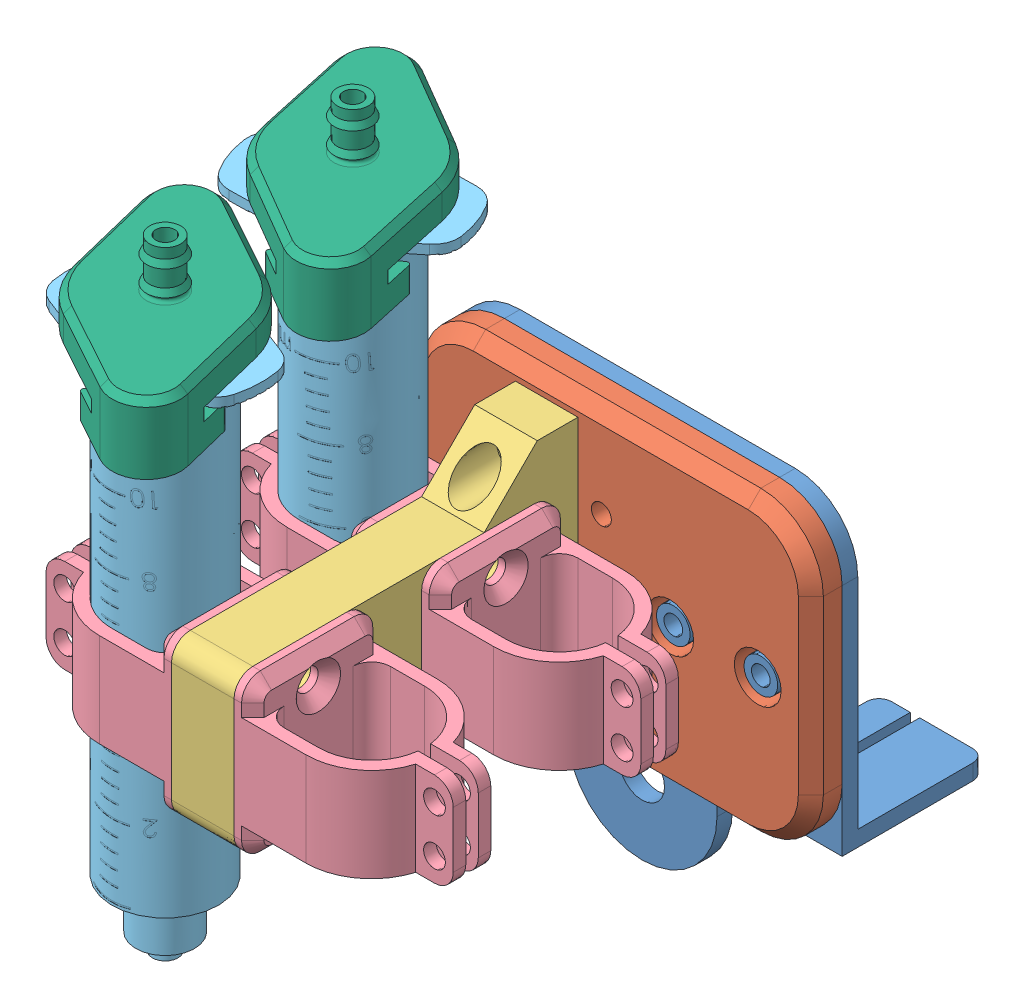
SolidWorks assembly quad-syringe, configuration Default. Lengths in mm.
Overall size (81.52 103.23 96.96).
11 component instances, 6 part files, 25 mates.
Components (placement in the parent):
- ender-3-bracket-1: ender-3-bracket [Default] at origin size (64 64 27.4)
- ender-3-quad-mount-1: ender-3-quad-mount [Default] at (37.5919 51.2294 2.5) x (1 0 0) z (0 -1 0) size (64 5 47.5)
- ender-3-syringe-mount-1: ender-3-syringe-mount [Default] at (-10.25 8.2 7.5) x (1 0 0) z (0 -1 0) size (10 55 42)
- syringe-holder-10ml-alt-1: syringe-holder-10ml-alt [Default] at (-15.25 8.2 52) x (0 0 1) z (-1 0 0) size (21 25 27.56)
- syringe-holder-10ml-alt-2: syringe-holder-10ml-alt [Default] at (-15.25 8.2 22) x (0 0 1) z (-1 0 0) size (21 25 27.56)
- syringe-holder-10ml-alt-3: syringe-holder-10ml-alt [Default] at (-5.25 8.2 22) x (0 0 -1) z (1 0 0) size (21 25 27.56)
- syringe-holder-10ml-alt-4: syringe-holder-10ml-alt [Default] at (-5.25 8.2 52) x (0 0 -1) z (1 0 0) size (21 25 27.56)
- syringe-cylinder-10ml-1: syringe-cylinder-10ml [Default] at (-26.75 53.3373 52) x (0 -1 0) z (-0.039342 0 0.999226) size (86.5 31 20)
- syringe-adapter-10ml-v3-1: syringe-adapter-10ml-v3 [Default] at (-26.75 58.3373 52) x (0.793052 0 -0.609153) z (0.609153 0 0.793052) size (24 18.62 43.5)
- syringe-cylinder-10ml-2: syringe-cylinder-10ml [Default] at (-26.75 57.4472 22) x (0 -1 0) z (0.339425 0 0.940633) size (86.5 31 20)
- syringe-adapter-10ml-v3-2: syringe-adapter-10ml-v3 [Default] at (-26.75 62.4472 22) x (0.808514 0 -0.588477) z (0.588477 0 0.808514) size (24 18.62 43.5)
Mates (geometry in assembly coordinates):
- Coincident2: coincident anti-aligned: plane of ender-3-bracket-1 through (0 -20 2.5) normal (0 0 1); plane of ender-3-quad-mount-1 through (37.5919 51.2294 2.5) normal (0 0 -1)
- Parallel1: parallel anti-aligned: plane of ender-3-quad-mount-1 through (37.5919 51.2294 2.5) normal (0 -1 0)
- Coincident4: coincident anti-aligned: plane of ender-3-quad-mount-1 through (37.5919 51.2294 7.5) normal (0 0 1); plane of ender-3-syringe-mount-1 through (-10.25 8.2 7.5) normal (0 0 -1)
- Concentric1: concentric anti-aligned: cylinder of ender-3-quad-mount-1 through (-10.25 24.2 7.5) axis (0 0 -1) radius 1.6; cylinder of ender-3-syringe-mount-1 through (-10.25 24.2 7.5) axis (0 0 1) radius 1.75
- Concentric2: concentric anti-aligned: cylinder of ender-3-quad-mount-1 through (-10.25 -7.8 7.5) axis (0 0 -1) radius 1.6; cylinder of ender-3-syringe-mount-1 through (-10.25 -7.8 7.5) axis (0 0 1) radius 1.75
- Coincident5: coincident anti-aligned: plane of ender-3-syringe-mount-1 through (-15.25 29.2 10.5) normal (-1 0 0); plane of syringe-holder-10ml-alt-1 through (-15.25 8.2 52) normal (1 0 0)
- Coincident6: coincident aligned: plane of ender-3-bracket-1 through (-32 0 0) normal (-1 0 0); plane of ender-3-quad-mount-1 through (-32 32 7.5) normal (-1 0 0)
- Coincident7: coincident aligned: plane of ender-3-bracket-1 through (-12 32 2.5) normal (0 1 0); plane of ender-3-quad-mount-1 through (-32 32 7.5) normal (0 1 0)
- Coincident8: coincident aligned: plane of ender-3-syringe-mount-1 through (-10.25 8.2 62.5) normal (0 0 1); plane of syringe-holder-10ml-alt-1 through (-18.25 20.7 62.5) normal (0 0 1)
- Coincident9: coincident aligned: plane of ender-3-syringe-mount-1 through (-15.25 20.7 62.5) normal (0 1 0); plane of syringe-holder-10ml-alt-1 through (-18.25 20.7 41.5) normal (0 1 0)
- Coincident10: coincident anti-aligned: plane of ender-3-syringe-mount-1 through (-15.25 29.2 10.5) normal (-1 0 0); plane of syringe-holder-10ml-alt-2 through (-15.25 8.2 22) normal (1 0 0)
- Coincident12: coincident aligned: plane of ender-3-syringe-mount-1 through (-15.25 20.7 62.5) normal (0 1 0); plane of syringe-holder-10ml-alt-2 through (-18.25 20.7 11.5) normal (0 1 0)
- Coincident13: coincident aligned: plane of syringe-holder-10ml-alt-3 through (-5.25 8.2 22) normal (-1 0 0); plane of syringe-holder-10ml-alt-4 through (-5.25 8.2 52) normal (-1 0 0)
- Coincident14: coincident anti-aligned: plane of ender-3-syringe-mount-1 through (-5.25 29.2 10.5) normal (1 0 0); plane of syringe-holder-10ml-alt-3 through (-5.25 8.2 22) normal (-1 0 0)
- Coincident15: coincident aligned: plane of syringe-holder-10ml-alt-3 through (-2.25 20.7 32.5) normal (0 1 0); plane of syringe-holder-10ml-alt-4 through (-2.25 20.7 62.5) normal (0 1 0)
- Coincident16: coincident aligned: plane of ender-3-syringe-mount-1 through (-10.25 8.2 62.5) normal (0 0 1); plane of syringe-holder-10ml-alt-4 through (-2.25 20.7 62.5) normal (0 0 1)
- Coincident18: coincident aligned: plane of ender-3-syringe-mount-1 through (-15.25 20.7 62.5) normal (0 1 0); plane of syringe-holder-10ml-alt-4 through (-2.25 20.7 62.5) normal (0 1 0)
- Concentric3: concentric anti-aligned: cylinder of syringe-holder-10ml-alt-1 through (-26.75 0.7 52) axis (0 1 0) radius 8.5; cylinder of syringe-cylinder-10ml-1 through (-26.75 -50.1842 52) axis (0 -1 0) radius 8.5
- Coincident19: coincident anti-aligned: plane of syringe-cylinder-10ml-1 through (-19.4557 53.3373 52.2872) normal (0 1 0); plane of syringe-adapter-10ml-v3-1 through (-25.8363 53.3373 53.1896) normal (0 -1 0)
- Concentric4: concentric anti-aligned: cylinder of syringe-cylinder-10ml-1 through (-26.75 -50.1842 52) axis (0 -1 0) radius 8.5; cylinder of syringe-adapter-10ml-v3-1 through (-26.75 66.2173 52) axis (0 1 0) radius 2.5
- Concentric5: concentric anti-aligned: cylinder of ender-3-syringe-mount-1 through (-5.25 15.7 22) axis (-1 0 0) radius 2; cylinder of syringe-holder-10ml-alt-2 through (-18.25 15.7 22) axis (1 0 0) radius 1.75
- Concentric6: concentric anti-aligned: cylinder of syringe-holder-10ml-alt-2 through (-26.75 0.7 22) axis (0 1 0) radius 8.5; cylinder of syringe-cylinder-10ml-2 through (-26.75 -46.0743 22) axis (0 -1 0) radius 8.5
- Concentric7: concentric anti-aligned: cylinder of syringe-cylinder-10ml-2 through (-26.75 -46.0743 22) axis (0 -1 0) radius 8.5; cylinder of syringe-adapter-10ml-v3-2 through (-26.75 70.3272 22) axis (0 1 0) radius 2.5
- Coincident20: coincident anti-aligned: plane of syringe-cylinder-10ml-2 through (-19.8834 57.4472 19.5222) normal (0 1 0); plane of syringe-adapter-10ml-v3-2 through (-25.8673 57.4472 23.2128) normal (0 -1 0)
- Concentric8: concentric aligned: circle of ender-3-syringe-mount-1; cylinder of syringe-holder-10ml-alt-3 through (-2.25 15.7 22) axis (-1 0 0) radius 1.75
